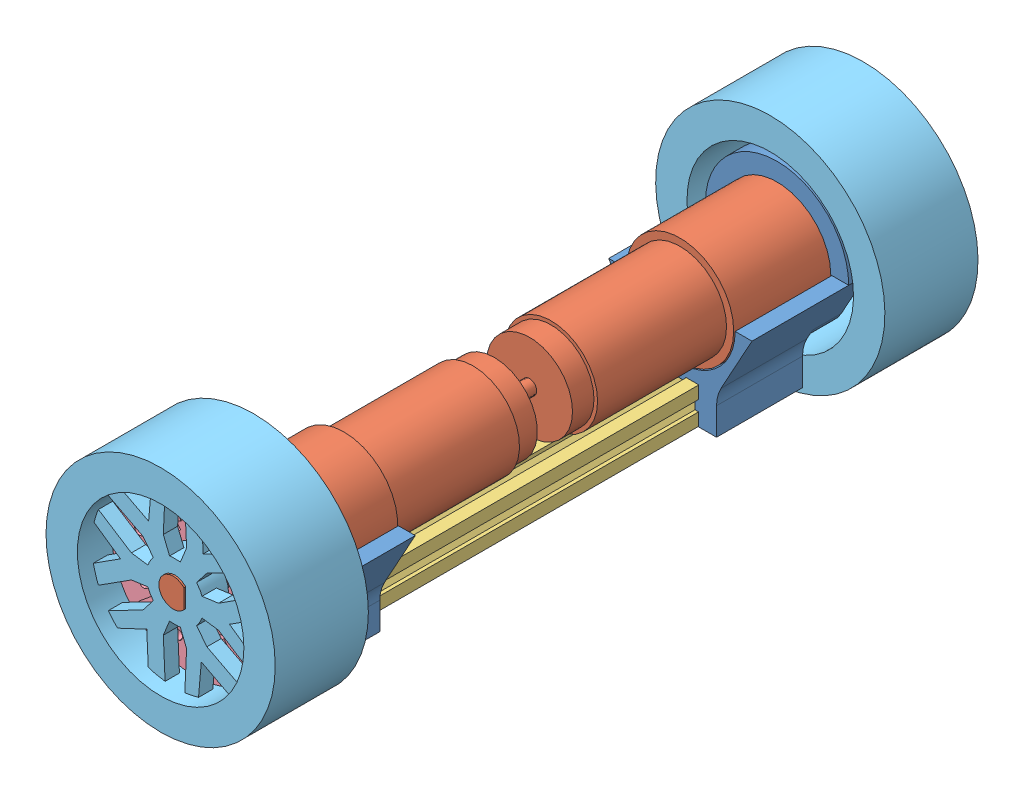
SolidWorks assembly SmallRobotMotorBlock, configuration Default. Lengths in mm.
Overall size (90.42 90.42 196.2).
8 component instances, 5 part files, 18 mates.
Components (placement in the parent):
- SmallRobotMotorSupport2018-1: SmallRobotMotorSupport2018 [Default] at (26.0815 36.3231 11.9257) size (40 48.2 32)
- 2642W_CR_with_30-1S-1: 2642W_CR_with_30-1S [Défaut] at (26.0815 36.3231 -38.9743) x (0 0 1) z (0 1 0) size (98.5 30 30)
- Makerbeam50-1000mm-1: Makerbeam50-1000mm [138mm] at (26.0815 13.1731 -104.0743) size (10 10 138)
- 2642W_CR_with_30-1S-2: 2642W_CR_with_30-1S [Défaut] at (26.0815 36.3231 -31.1743) x (0 0 -1) z (1 0 0) size (98.5 30 30)
- SmallRobotMotorSupport2018-2: SmallRobotMotorSupport2018 [Default] at (26.0815 36.3231 -82.0743) x (-1 0 0) z (0 0 -1) size (40 48.2 32)
- SmallRobotWheelHub-1: SmallRobotWheelHub [Default] at (26.0815 36.3231 37.6257) x (0.99504 0.099476 0) z (0.099476 -0.99504 0) size (47 17.4 47)
- Wheel-Traction-63x26mm-1: Wheel-Traction-63x26mm [Défaut] at (26.0815 36.3231 37.0257) size (64 64 26)
- Wheel-Traction-63x26mm-2: Wheel-Traction-63x26mm [Défaut] at (26.0815 36.3231 -107.1743) x (-0.738363 -0.674404 0) z (0 0 -1) size (64 64 26)
Mates (geometry in assembly coordinates):
- Concentric1: concentric aligned: cylinder of SmallRobotMotorSupport2018-1 through (26.0815 36.3231 43.9257) axis (0 0 -1) radius 9.1; cylinder of 2642W_CR_with_30-1S-1 through (26.0815 36.3231 -38.9743) axis (0 0 -1) radius 9
- Coincident1: coincident anti-aligned: plane of SmallRobotMotorSupport2018-1 through (26.0815 36.3231 38.9257) normal (0 0 -1); plane of 2642W_CR_with_30-1S-1 through (35.0815 36.3231 38.9257) normal (0 0 1)
- Concentric2: concentric aligned: cylinder of SmallRobotMotorSupport2018-1 through (26.0815 49.3231 11.9257) axis (0 0 1) radius 1.35; cylinder of 2642W_CR_with_30-1S-1 through (26.0815 49.3231 35.9257) axis (0 0 1) radius 1.5
- Coincident2: coincident anti-aligned: plane of SmallRobotMotorSupport2018-1 through (26.0815 36.3231 33.9257) normal (0 0 -1); plane of Makerbeam50-1000mm-1 through (26.0815 13.1731 33.9257) normal (0 0 1)
- Concentric4: concentric aligned: cylinder of SmallRobotMotorSupport2018-1 through (26.0815 13.1731 35.9257) axis (0 0 -1) radius 1.6; cylinder of Makerbeam50-1000mm-1 through (26.0815 13.1731 33.9257) axis (0 0 -1) radius 1.25
- Parallel1: parallel aligned: plane of SmallRobotMotorSupport2018-1 through (20.9815 8.1231 43.9257) normal (0 -1 0); plane of Makerbeam50-1000mm-1 through (27.5815 8.1731 33.9257) normal (0 -1 0)
- Concentric5: concentric aligned: circle of Makerbeam50-1000mm-1; cylinder of SmallRobotMotorSupport2018-2 through (26.0815 13.1731 -106.0743) axis (0 0 1) radius 1.6
- Parallel2: parallel aligned: plane of Makerbeam50-1000mm-1 through (27.5815 8.1731 33.9257) normal (0 -1 0); plane of SmallRobotMotorSupport2018-2 through (31.1815 8.1231 -114.0743) normal (0 -1 0)
- Coincident6: coincident anti-aligned: plane of Makerbeam50-1000mm-1 through (26.0815 13.1731 -104.0743) normal (0 0 -1); plane of SmallRobotMotorSupport2018-2 through (26.0815 36.3231 -104.0743) normal (0 0 1)
- Concentric6: concentric aligned: cylinder of 2642W_CR_with_30-1S-2 through (26.0815 36.3231 -31.1743) axis (0 0 1) radius 9; cylinder of SmallRobotMotorSupport2018-2 through (26.0815 36.3231 -114.0743) axis (0 0 1) radius 9.1
- Concentric7: concentric aligned: circle of 2642W_CR_with_30-1S-2; cylinder of SmallRobotMotorSupport2018-2 through (26.0815 49.3231 -82.0743) axis (0 0 -1) radius 1.35
- Coincident7: coincident anti-aligned: plane of 2642W_CR_with_30-1S-2 through (26.0815 45.3231 -109.0743) normal (0 0 -1); plane of SmallRobotMotorSupport2018-2 through (26.0815 36.3231 -109.0743) normal (0 0 1)
- Concentric8: concentric anti-aligned: cylinder of 2642W_CR_with_30-1S-1 through (26.0815 36.3231 -38.9743) axis (0 0 -1) radius 4; circle of SmallRobotWheelHub-1
- Coincident9: coincident anti-aligned: plane of SmallRobotWheelHub-1 through (26.0815 36.3231 55.0257) normal (0 0 1); plane of Wheel-Traction-63x26mm-1 through (26.0815 36.3231 55.0257) normal (0 0 -1)
- Concentric9: concentric anti-aligned: cylinder of 2642W_CR_with_30-1S-1 through (26.0815 36.3231 -38.9743) axis (0 0 -1) radius 4; cylinder of Wheel-Traction-63x26mm-1 through (26.0815 36.3231 37.0257) axis (0 0 1) radius 2
- Distance1: distance = 0.5 mm aligned: plane of 2642W_CR_with_30-1S-1 through (26.0815 36.3231 59.5257) normal (0 0 1); plane of Wheel-Traction-63x26mm-1 through (26.0815 36.3231 59.0257) normal (0 0 1)
- Concentric10: concentric anti-aligned: cylinder of 2642W_CR_with_30-1S-2 through (26.0815 36.3231 -31.1743) axis (0 0 1) radius 4; cylinder of Wheel-Traction-63x26mm-2 through (26.0815 36.3231 -107.1743) axis (0 0 -1) radius 2
- Distance2: distance = 0.5 mm aligned: plane of 2642W_CR_with_30-1S-2 through (26.0815 36.3231 -129.6743) normal (0 0 -1); plane of Wheel-Traction-63x26mm-2 through (26.0815 36.3231 -129.1743) normal (0 0 -1)
